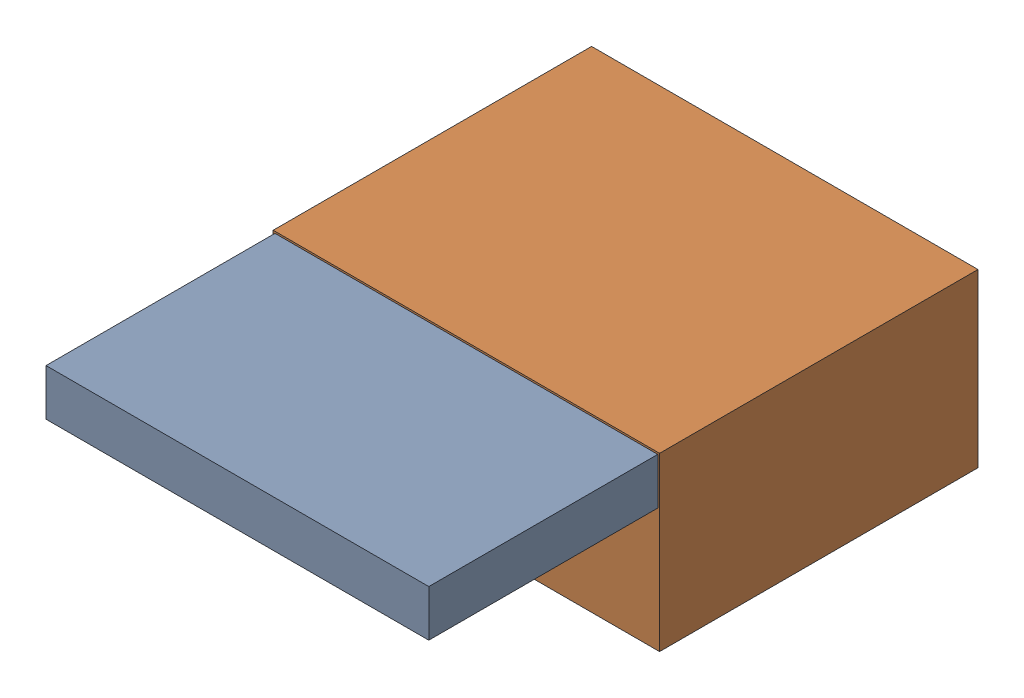
SolidWorks assembly FET-RL_1, configuration Default. Lengths in mm.
Overall size (10.8 4.8 15.3).
4 component instances, 2 part files, 0 mates.
Components (placement in the parent):
- 1017093232-1: 1017093232 [Default] at (88.9 133.01 12.9) size (10.7 1.3 6.4)
  - Extruded-1: Extruded [Default] at origin size (10.7 1.3 6.4)
- 1017093616-1: 1017093616 [Default] at (88.9 131.31 4) size (10.8 4.8 8.9)
  - Extruded_2-1: Extruded_2 [Default] at origin size (10.8 4.8 8.9)
